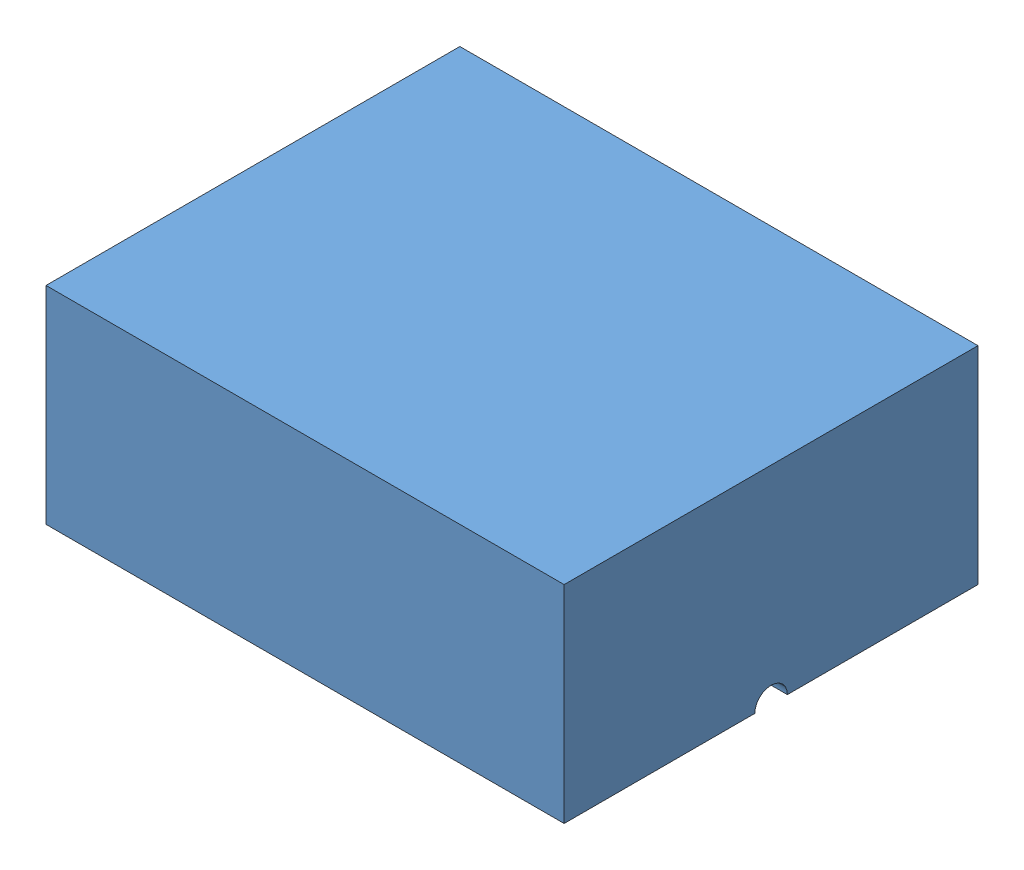
SolidWorks assembly Assem3, configuration Default. Lengths in mm.
Overall size (31.8 12.7 25.4).
2 component instances, 2 part files, 0 mates.
Components (placement in the parent):
- outer-1: outer [Default] at origin size (31.8 12.7 25.4)
- inner-1: inner [Default] at (0 0.0002 0) size (24 6 12)
